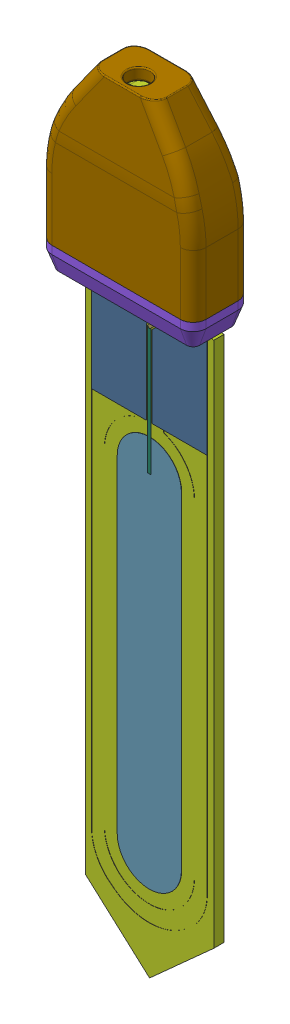
SolidWorks assembly Assem1, configuration Default. Lengths in mm.
Overall size (24 122.5 9.11).
134 component instances, 117 part files, 5 mates.
Components (placement in the parent):
- Soile_Moisture_Sensor_Wired.step-1: Soile_Moisture_Sensor_Wired.step [Default] at (-16.8266 161.5722 83.1683) size (20 119 3.44)
  - C_0603_1608Metric.step-1: C_0603_1608Metric.step [Default] at (57.8674 -40.1741 1.65) x (0 -1 0) z (0 0 1) size (1.6 0.8 0.8)
    - C_0603_1608Metric-0.step-1: C_0603_1608Metric-0.step [Default] at origin size (1.6 0.8 0.8)
  - R_0603_1608Metric.step-1: R_0603_1608Metric.step [Default] at (59.3914 -40.1741 1.65) x (0 1 0) z (0 0 1) size (1.6 0.8 0.45)
    - R_0603_1608Metric-1.step-1: R_0603_1608Metric-1.step [Default] at origin size (1.6 0.8 0.45)
  - C_0603_1608Metric.step-2: C_0603_1608Metric.step [Default] at (51.496 -38.6061 1.65) x (-1 0 0) z (0 0 1) size (1.6 0.8 0.8)
    - C_0603_1608Metric-0.step-1: C_0603_1608Metric-0.step [Default] at origin size (1.6 0.8 0.8)
  - D_MiniMELF.step-1: D_MiniMELF.step [Default] at (55.8354 -41.3171 1.65) x (0 -1 0) z (0 0 1) size (3.6 1.4 1.4)
    - D_MiniMELF_Standard.step-1: D_MiniMELF_Standard.step [Default] at origin size (3.6 1.4 1.4)
  - SOIC-8_3.9x4.9mm_P1.27mm.step-1: SOIC-8_3.9x4.9mm_P1.27mm.step [Default] at (49.271 -42.2061 1.65) x (-1 0 0) z (0 0 1) size (6 4.9 1.75)
    - SOIC_8_39x49mm_P127mm.step-1: SOIC_8_39x49mm_P127mm.step [Default] at origin size (6 4.9 1.75)
  - C_0603_1608Metric.step-3: C_0603_1608Metric.step [Default] at (48.446 -38.6061 1.65) x (-1 0 0) z (0 0 1) size (1.6 0.8 0.8)
    - C_0603_1608Metric-0.step-1: C_0603_1608Metric-0.step [Default] at origin size (1.6 0.8 0.8)
  - C_0603_1608Metric.step-4: C_0603_1608Metric.step [Default] at (45.396 -38.6061 1.65) size (1.6 0.8 0.8)
    - C_0603_1608Metric-0.step-1: C_0603_1608Metric-0.step [Default] at origin size (1.6 0.8 0.8)
  - R_0603_1608Metric.step-2: R_0603_1608Metric.step [Default] at (53.8743 -42.4895 1.65) x (0 -1 0) z (0 0 1) size (1.6 0.8 0.45)
    - R_0603_1608Metric-1.step-1: R_0603_1608Metric-1.step [Default] at origin size (1.6 0.8 0.45)
  - R_0603_1608Metric.step-3: R_0603_1608Metric.step [Default] at (44.671 -40.9961 1.65) x (0 -1 0) z (0 0 1) size (1.6 0.8 0.45)
    - R_0603_1608Metric-1.step-1: R_0603_1608Metric-1.step [Default] at origin size (1.6 0.8 0.45)
  - R_0603_1608Metric.step-4: R_0603_1608Metric.step [Default] at (44.671 -44.0461 1.65) x (0 -1 0) z (0 0 1) size (1.6 0.8 0.45)
    - R_0603_1608Metric-1.step-1: R_0603_1608Metric-1.step [Default] at origin size (1.6 0.8 0.45)
  - Soile_Moisture_Sensor_Wired_track_1.step-1: Soile_Moisture_Sensor_Wired_track_1.step [Default] at origin size (0.68 0.68 0.03)
  - Soile_Moisture_Sensor_Wired_track_2.step-1: Soile_Moisture_Sensor_Wired_track_2.step [Default] at origin size (0.51 4.78 0.03)
  - Soile_Moisture_Sensor_Wired_track_3.step-1: Soile_Moisture_Sensor_Wired_track_3.step [Default] at origin size (0.51 1.68 0.03)
  - Soile_Moisture_Sensor_Wired_track_4.step-1: Soile_Moisture_Sensor_Wired_track_4.step [Default] at origin size (1.03 1.03 0.03)
  - Soile_Moisture_Sensor_Wired_track_5.step-1: Soile_Moisture_Sensor_Wired_track_5.step [Default] at origin size (3.86 3.86 0.03)
  - Soile_Moisture_Sensor_Wired_track_6.step-1: Soile_Moisture_Sensor_Wired_track_6.step [Default] at origin size (0.51 2.29 0.03)
  - Soile_Moisture_Sensor_Wired_track_7.step-1: Soile_Moisture_Sensor_Wired_track_7.step [Default] at origin size (0.27 0.27 0.03)
  - Soile_Moisture_Sensor_Wired_track_8.step-1: Soile_Moisture_Sensor_Wired_track_8.step [Default] at origin size (1.75 0.25 0.03)
  - Soile_Moisture_Sensor_Wired_track_9.step-1: Soile_Moisture_Sensor_Wired_track_9.step [Default] at origin size (0.51 3.58 0.03)
  - Soile_Moisture_Sensor_Wired_track_10.step-1: Soile_Moisture_Sensor_Wired_track_10.step [Default] at origin size (1.98 0.51 0.03)
  - Soile_Moisture_Sensor_Wired_track_11.step-1: Soile_Moisture_Sensor_Wired_track_11.step [Default] at origin size (1.71 1.71 0.03)
  - Soile_Moisture_Sensor_Wired_track_12.step-1: Soile_Moisture_Sensor_Wired_track_12.step [Default] at origin size (0.56 0.56 0.03)
  - Soile_Moisture_Sensor_Wired_track_13.step-1: Soile_Moisture_Sensor_Wired_track_13.step [Default] at origin size (0.68 0.68 0.03)
  - Soile_Moisture_Sensor_Wired_track_14.step-1: Soile_Moisture_Sensor_Wired_track_14.step [Default] at origin size (2.37 0.51 0.03)
  - Soile_Moisture_Sensor_Wired_track_15.step-1: Soile_Moisture_Sensor_Wired_track_15.step [Default] at origin size (0.53 0.51 0.03)
  - Soile_Moisture_Sensor_Wired_track_16.step-1: Soile_Moisture_Sensor_Wired_track_16.step [Default] at origin size (0.51 1.35 0.03)
  - Soile_Moisture_Sensor_Wired_track_17.step-1: Soile_Moisture_Sensor_Wired_track_17.step [Default] at origin size (1.36 1.36 0.03)
  - Soile_Moisture_Sensor_Wired_track_18.step-1: Soile_Moisture_Sensor_Wired_track_18.step [Default] at origin size (2.21 0.51 0.03)
  - Soile_Moisture_Sensor_Wired_track_19.step-1: Soile_Moisture_Sensor_Wired_track_19.step [Default] at origin size (1.91 1.91 0.03)
  - Soile_Moisture_Sensor_Wired_track_20.step-1: Soile_Moisture_Sensor_Wired_track_20.step [Default] at origin size (0.51 2.02 0.03)
  - Soile_Moisture_Sensor_Wired_track_21.step-1: Soile_Moisture_Sensor_Wired_track_21.step [Default] at origin size (1.78 1.78 0.03)
  - Soile_Moisture_Sensor_Wired_track_22.step-1: Soile_Moisture_Sensor_Wired_track_22.step [Default] at origin size (0.56 0.56 0.03)
  - Soile_Moisture_Sensor_Wired_track_23.step-1: Soile_Moisture_Sensor_Wired_track_23.step [Default] at origin size (1.23 0.51 0.03)
  - Soile_Moisture_Sensor_Wired_track_24.step-1: Soile_Moisture_Sensor_Wired_track_24.step [Default] at origin size (2.48 0.51 0.03)
  - Soile_Moisture_Sensor_Wired_track_25.step-1: Soile_Moisture_Sensor_Wired_track_25.step [Default] at origin size (2.22 0.51 0.03)
  - Soile_Moisture_Sensor_Wired_track_26.step-1: Soile_Moisture_Sensor_Wired_track_26.step [Default] at origin size (4.27 4.27 0.03)
  - Soile_Moisture_Sensor_Wired_track_27.step-1: Soile_Moisture_Sensor_Wired_track_27.step [Default] at origin size (0.51 8.11 0.03)
  - Soile_Moisture_Sensor_Wired_track_28.step-1: Soile_Moisture_Sensor_Wired_track_28.step [Default] at origin size (10 61 0.03)
  - Soile_Moisture_Sensor_Wired_track_29.step-1: Soile_Moisture_Sensor_Wired_track_29.step [Default] at origin size (0.51 20.37 0.03)
  - Soile_Moisture_Sensor_Wired_track_30.step-1: Soile_Moisture_Sensor_Wired_track_30.step [Default] at origin size (0.76 0.76 0.03)
  - Soile_Moisture_Sensor_Wired_track_31.step-1: Soile_Moisture_Sensor_Wired_track_31.step [Default] at origin size (0.52 0.52 0.03)
  - Soile_Moisture_Sensor_Wired_track_32.step-1: Soile_Moisture_Sensor_Wired_track_32.step [Default] at origin size (0.6 0.6 0.03)
  - Soile_Moisture_Sensor_Wired_track_33.step-1: Soile_Moisture_Sensor_Wired_track_33.step [Default] at origin size (2.54 0.51 0.03)
  - Soile_Moisture_Sensor_Wired_track_34.step-1: Soile_Moisture_Sensor_Wired_track_34.step [Default] at origin size (0.51 1.19 0.03)
  - Soile_Moisture_Sensor_Wired_track_35.step-1: Soile_Moisture_Sensor_Wired_track_35.step [Default] at origin size (0.81 0.81 0.03)
  - Soile_Moisture_Sensor_Wired_track_36.step-1: Soile_Moisture_Sensor_Wired_track_36.step [Default] at origin size (1.81 0.51 0.03)
  - Soile_Moisture_Sensor_Wired_track_37.step-1: Soile_Moisture_Sensor_Wired_track_37.step [Default] at origin size (1.03 0.51 0.03)
  - Soile_Moisture_Sensor_Wired_track_38.step-1: Soile_Moisture_Sensor_Wired_track_38.step [Default] at origin size (0.51 1.22 0.03)
  - Soile_Moisture_Sensor_Wired_zone_1.step-1: Soile_Moisture_Sensor_Wired_zone_1.step [Default] at origin size (4.42 2.44 0.05)
  - Soile_Moisture_Sensor_Wired_zone_2.step-1: Soile_Moisture_Sensor_Wired_zone_2.step [Default] at origin size (0.77 0.65 0.05)
  - Soile_Moisture_Sensor_Wired_zone_3.step-1: Soile_Moisture_Sensor_Wired_zone_3.step [Default] at origin size (0.58 0.42 0.04)
  - Soile_Moisture_Sensor_Wired_zone_4.step-1: Soile_Moisture_Sensor_Wired_zone_4.step [Default] at origin size (19 43.5 0.04)
  - Soile_Moisture_Sensor_Wired_zone_5.step-1: Soile_Moisture_Sensor_Wired_zone_5.step [Default] at origin size (2.53 0.39 0.05)
  - Soile_Moisture_Sensor_Wired_zone_6.step-1: Soile_Moisture_Sensor_Wired_zone_6.step [Default] at origin size (0.81 1.08 0.04)
  - Soile_Moisture_Sensor_Wired_zone_7.step-1: Soile_Moisture_Sensor_Wired_zone_7.step [Default] at origin size (18 67.54 0.05)
  - Soile_Moisture_Sensor_Wired_zone_8.step-1: Soile_Moisture_Sensor_Wired_zone_8.step [Default] at origin size (19 26.5 0.04)
  - Soile_Moisture_Sensor_Wired_pad_1.step-1: Soile_Moisture_Sensor_Wired_pad_1.step [Default] at origin size (0.95 0.9 0.03)
  - Soile_Moisture_Sensor_Wired_pad_2.step-1: Soile_Moisture_Sensor_Wired_pad_2.step [Default] at origin size (0.95 0.9 0.03)
  - Soile_Moisture_Sensor_Wired_pad_3.step-1: Soile_Moisture_Sensor_Wired_pad_3.step [Default] at origin size (0.95 0.8 0.03)
  - Soile_Moisture_Sensor_Wired_pad_4.step-1: Soile_Moisture_Sensor_Wired_pad_4.step [Default] at origin size (0.95 0.8 0.03)
  - Soile_Moisture_Sensor_Wired_pad_5.step-1: Soile_Moisture_Sensor_Wired_pad_5.step [Default] at origin size (0.9 0.95 0.03)
  - Soile_Moisture_Sensor_Wired_pad_6.step-1: Soile_Moisture_Sensor_Wired_pad_6.step [Default] at origin size (0.9 0.95 0.03)
  - Soile_Moisture_Sensor_Wired_pad_7.step-1: Soile_Moisture_Sensor_Wired_pad_7.step [Default] at origin size (1.7 1.3 0.03)
  - Soile_Moisture_Sensor_Wired_pad_8.step-1: Soile_Moisture_Sensor_Wired_pad_8.step [Default] at origin size (1.7 1.3 0.03)
  - Soile_Moisture_Sensor_Wired_pad_9.step-1: Soile_Moisture_Sensor_Wired_pad_9.step [Default] at origin size (1.7 1.69 0.03)
  - Soile_Moisture_Sensor_Wired_pad_10.step-1: Soile_Moisture_Sensor_Wired_pad_10.step [Default] at origin size (1.7 1.69 0.03)
  - Soile_Moisture_Sensor_Wired_pad_11.step-1: Soile_Moisture_Sensor_Wired_pad_11.step [Default] at origin size (1 1 1.67)
  - Soile_Moisture_Sensor_Wired_pad_12.step-1: Soile_Moisture_Sensor_Wired_pad_12.step [Default] at origin size (1.7 3 0.03)
  - Soile_Moisture_Sensor_Wired_pad_13.step-1: Soile_Moisture_Sensor_Wired_pad_13.step [Default] at origin size (1.7 1.69 0.03)
  - Soile_Moisture_Sensor_Wired_pad_14.step-1: Soile_Moisture_Sensor_Wired_pad_14.step [Default] at origin size (1.7 1.69 0.03)
  - Soile_Moisture_Sensor_Wired_pad_15.step-1: Soile_Moisture_Sensor_Wired_pad_15.step [Default] at origin size (1 1 1.67)
  - Soile_Moisture_Sensor_Wired_pad_16.step-1: Soile_Moisture_Sensor_Wired_pad_16.step [Default] at origin size (1.7 3 0.03)
  - Soile_Moisture_Sensor_Wired_pad_17.step-1: Soile_Moisture_Sensor_Wired_pad_17.step [Default] at origin size (1.7 1.69 0.03)
  - Soile_Moisture_Sensor_Wired_pad_18.step-1: Soile_Moisture_Sensor_Wired_pad_18.step [Default] at origin size (1.7 1.69 0.03)
  - Soile_Moisture_Sensor_Wired_pad_19.step-1: Soile_Moisture_Sensor_Wired_pad_19.step [Default] at origin size (1 1 1.67)
  - Soile_Moisture_Sensor_Wired_pad_20.step-1: Soile_Moisture_Sensor_Wired_pad_20.step [Default] at origin size (1.7 3 0.03)
  - Soile_Moisture_Sensor_Wired_pad_21.step-1: Soile_Moisture_Sensor_Wired_pad_21.step [Default] at origin size (1.95 0.6 0.03)
  - Soile_Moisture_Sensor_Wired_pad_22.step-1: Soile_Moisture_Sensor_Wired_pad_22.step [Default] at origin size (1.95 0.6 0.03)
  - Soile_Moisture_Sensor_Wired_pad_23.step-1: Soile_Moisture_Sensor_Wired_pad_23.step [Default] at origin size (1.95 0.6 0.03)
  - Soile_Moisture_Sensor_Wired_pad_24.step-1: Soile_Moisture_Sensor_Wired_pad_24.step [Default] at origin size (1.95 0.6 0.03)
  - Soile_Moisture_Sensor_Wired_pad_25.step-1: Soile_Moisture_Sensor_Wired_pad_25.step [Default] at origin size (1.95 0.6 0.03)
  - Soile_Moisture_Sensor_Wired_pad_26.step-1: Soile_Moisture_Sensor_Wired_pad_26.step [Default] at origin size (1.95 0.6 0.03)
  - Soile_Moisture_Sensor_Wired_pad_27.step-1: Soile_Moisture_Sensor_Wired_pad_27.step [Default] at origin size (1.95 0.6 0.03)
  - Soile_Moisture_Sensor_Wired_pad_28.step-1: Soile_Moisture_Sensor_Wired_pad_28.step [Default] at origin size (1.95 0.6 0.03)
  - Soile_Moisture_Sensor_Wired_pad_29.step-1: Soile_Moisture_Sensor_Wired_pad_29.step [Default] at (59.381 -46.9487 1.6) size (1 1 0.03)
  - Soile_Moisture_Sensor_Wired_pad_30.step-1: Soile_Moisture_Sensor_Wired_pad_30.step [Default] at origin size (0.9 0.95 0.03)
  - Soile_Moisture_Sensor_Wired_pad_31.step-1: Soile_Moisture_Sensor_Wired_pad_31.step [Default] at origin size (0.9 0.95 0.03)
  - Soile_Moisture_Sensor_Wired_pad_32.step-1: Soile_Moisture_Sensor_Wired_pad_32.step [Default] at origin size (0.9 0.95 0.03)
  - Soile_Moisture_Sensor_Wired_pad_33.step-1: Soile_Moisture_Sensor_Wired_pad_33.step [Default] at origin size (0.9 0.95 0.03)
  - Soile_Moisture_Sensor_Wired_pad_34.step-1: Soile_Moisture_Sensor_Wired_pad_34.step [Default] at origin size (0.95 0.8 0.03)
  - Soile_Moisture_Sensor_Wired_pad_35.step-1: Soile_Moisture_Sensor_Wired_pad_35.step [Default] at origin size (0.95 0.8 0.03)
  - Soile_Moisture_Sensor_Wired_pad_36.step-1: Soile_Moisture_Sensor_Wired_pad_36.step [Default] at origin size (0.95 0.8 0.03)
  - Soile_Moisture_Sensor_Wired_pad_37.step-1: Soile_Moisture_Sensor_Wired_pad_37.step [Default] at origin size (0.95 0.8 0.03)
  - Soile_Moisture_Sensor_Wired_pad_38.step-1: Soile_Moisture_Sensor_Wired_pad_38.step [Default] at origin size (0.95 0.8 0.03)
  - Soile_Moisture_Sensor_Wired_pad_39.step-1: Soile_Moisture_Sensor_Wired_pad_39.step [Default] at origin size (0.95 0.8 0.03)
  - Soile_Moisture_Sensor_Wired_pad_40.step-1: Soile_Moisture_Sensor_Wired_pad_40.step [Default] at (44.381 -34.9487 1.6) size (1 1 0.03)
  - Soile_Moisture_Sensor_Wired_pad_41.step-1: Soile_Moisture_Sensor_Wired_pad_41.step [Default] at origin size (0.8 0.8 0.03)
  - Soile_Moisture_Sensor_Wired_pad_42.step-1: Soile_Moisture_Sensor_Wired_pad_42.step [Default] at origin size (0.8 0.8 0.03)
  - Soile_Moisture_Sensor_Wired_pad_43.step-1: Soile_Moisture_Sensor_Wired_pad_43.step [Default] at origin size (0.4 0.4 1.67)
  - Soile_Moisture_Sensor_Wired_pad_44.step-1: Soile_Moisture_Sensor_Wired_pad_44.step [Default] at origin size (0.8 0.8 0.03)
  - Soile_Moisture_Sensor_Wired_pad_45.step-1: Soile_Moisture_Sensor_Wired_pad_45.step [Default] at origin size (0.8 0.8 0.03)
  - Soile_Moisture_Sensor_Wired_pad_46.step-1: Soile_Moisture_Sensor_Wired_pad_46.step [Default] at origin size (0.4 0.4 1.67)
  - Soile_Moisture_Sensor_Wired_pad_47.step-1: Soile_Moisture_Sensor_Wired_pad_47.step [Default] at origin size (0.6 0.6 0.03)
  - Soile_Moisture_Sensor_Wired_pad_48.step-1: Soile_Moisture_Sensor_Wired_pad_48.step [Default] at origin size (0.6 0.6 0.03)
  - Soile_Moisture_Sensor_Wired_pad_49.step-1: Soile_Moisture_Sensor_Wired_pad_49.step [Default] at origin size (0.3 0.3 1.67)
  - Soile_Moisture_Sensor_Wired_pad_50.step-1: Soile_Moisture_Sensor_Wired_pad_50.step [Default] at origin size (0.6 0.6 0.03)
  - Soile_Moisture_Sensor_Wired_pad_51.step-1: Soile_Moisture_Sensor_Wired_pad_51.step [Default] at origin size (0.6 0.6 0.03)
  - Soile_Moisture_Sensor_Wired_pad_52.step-1: Soile_Moisture_Sensor_Wired_pad_52.step [Default] at origin size (0.3 0.3 1.67)
  - Soile_Moisture_Sensor_Wired_pad_53.step-1: Soile_Moisture_Sensor_Wired_pad_53.step [Default] at origin size (0.6 0.6 0.03)
  - Soile_Moisture_Sensor_Wired_pad_54.step-1: Soile_Moisture_Sensor_Wired_pad_54.step [Default] at origin size (0.6 0.6 0.03)
  - Soile_Moisture_Sensor_Wired_pad_55.step-1: Soile_Moisture_Sensor_Wired_pad_55.step [Default] at origin size (0.3 0.3 1.67)
  - Soile_Moisture_Sensor_Wired_pad_56.step-1: Soile_Moisture_Sensor_Wired_pad_56.step [Default] at origin size (0.6 0.6 0.03)
  - Soile_Moisture_Sensor_Wired_pad_57.step-1: Soile_Moisture_Sensor_Wired_pad_57.step [Default] at origin size (0.6 0.6 0.03)
  - Soile_Moisture_Sensor_Wired_pad_58.step-1: Soile_Moisture_Sensor_Wired_pad_58.step [Default] at origin size (0.3 0.3 1.67)
  - Soile_Moisture_Sensor_Wired_pad_59.step-1: Soile_Moisture_Sensor_Wired_pad_59.step [Default] at origin size (0.6 0.6 0.03)
  - Soile_Moisture_Sensor_Wired_pad_60.step-1: Soile_Moisture_Sensor_Wired_pad_60.step [Default] at origin size (0.6 0.6 0.03)
  - Soile_Moisture_Sensor_Wired_pad_61.step-1: Soile_Moisture_Sensor_Wired_pad_61.step [Default] at origin size (0.3 0.3 1.67)
  - Soile_Moisture_Sensor_Wired_pad_62.step-1: Soile_Moisture_Sensor_Wired_pad_62.step [Default] at origin size (0.6 0.6 0.03)
  - Soile_Moisture_Sensor_Wired_pad_63.step-1: Soile_Moisture_Sensor_Wired_pad_63.step [Default] at origin size (0.6 0.6 0.03)
  - Soile_Moisture_Sensor_Wired_pad_64.step-1: Soile_Moisture_Sensor_Wired_pad_64.step [Default] at origin size (0.3 0.3 1.67)
  - Soile_Moisture_Sensor_Wired_PCB.step-1: Soile_Moisture_Sensor_Wired_PCB.step [Default] at origin size (20 119 1.6)
- SoilSens-05_Base-1: SoilSens-05_Base [Default] at (35.3354 116.7673 81.0533) x (1 0 0) z (0 -1 0) size (24 9 10)
- SoilSens-05_Cap-1: SoilSens-05_Cap [Default] at (35.3354 115.7673 85.5533) x (1 0 0) z (0 1 0) size (24 9.11 26)
Mates (geometry in assembly coordinates):
- Coincident1: coincident anti-aligned: plane of Soile_Moisture_Sensor_Wired.step-1/Soile_Moisture_Sensor_Wired_zone_4.step-1 through (-16.8266 161.5722 84.8033) normal (0 0 1); plane of SoilSens-05_Base-1 through (25.2604 126.7673 84.8033) normal (0 0 -1)
- Coincident2: coincident anti-aligned: plane of Soile_Moisture_Sensor_Wired.step-1/Soile_Moisture_Sensor_Wired_PCB.step-1 through (25.2604 28.2712 83.1683) normal (-1 0 0); plane of SoilSens-05_Base-1 through (25.2604 126.7673 84.8033) normal (1 0 0)
- Coincident3: coincident anti-aligned: plane of SoilSens-05_Base-1 through (46.3354 115.7673 88.0533) normal (1 0 0); plane of SoilSens-05_Cap-1 through (46.3354 121.7673 82.0533) normal (-1 0 0)
- Coincident4: coincident anti-aligned: plane of SoilSens-05_Base-1 through (45.3354 115.7673 82.0533) normal (0 0 -1); plane of SoilSens-05_Cap-1 through (24.3354 121.7673 82.0533) normal (0 0 1)
- Coincident5: coincident anti-aligned: plane of SoilSens-05_Base-1 through (35.3354 115.7673 81.0533) normal (0 1 0); plane of SoilSens-05_Cap-1 through (35.3354 115.7673 85.5533) normal (0 -1 0)
